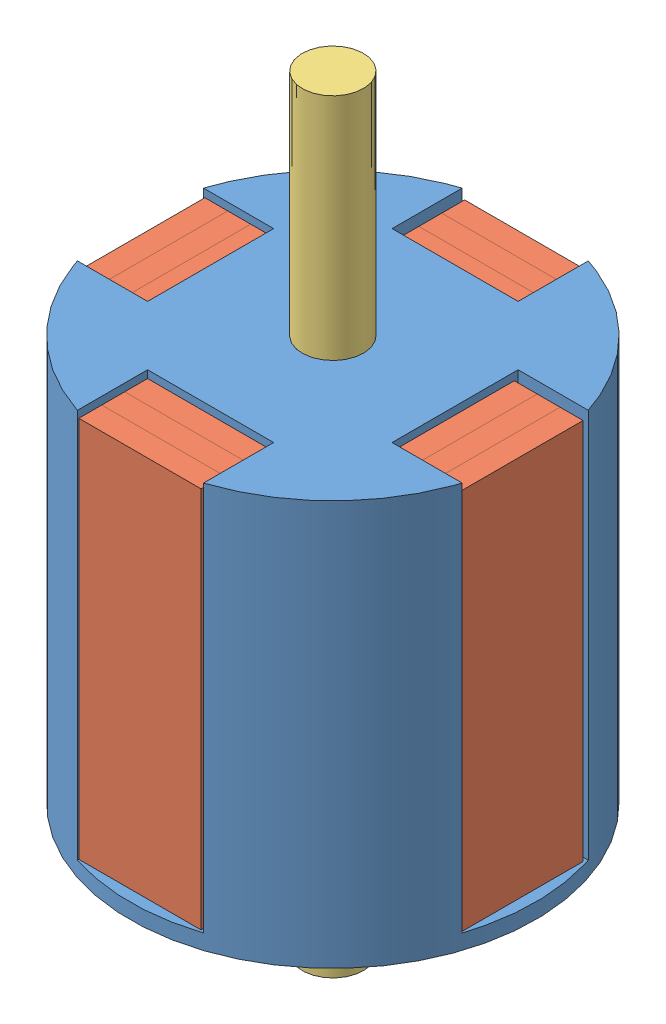
SolidWorks assembly rotor, configuration 默认. Lengths in mm.
Overall size (53 100 53).
14 component instances, 3 part files, 8 mates.
Components (placement in the parent):
- inner rotor-1: inner rotor [默认] at (-18.2401 -31.003 53.0001) size (53 53 53)
- magnet x12个 rectangular new-1: magnet x12个 rectangular new [默认] at (-18.4901 -6.003 72.0001) x (1 0 0) z (0 1 0) size (16 3 50)
- magnet x12个 rectangular new-2: magnet x12个 rectangular new [默认] at (-18.4901 -6.003 75.0001) x (1 0 0) z (0 1 0) size (16 3 50)
- magnet x12个 rectangular new-3: magnet x12个 rectangular new [默认] at (-18.4901 -6.003 78.0001) x (1 0 0) z (0 1 0) size (16 3 50)
- magnet x12个 rectangular new-4: magnet x12个 rectangular new [默认] at (-17.9901 -6.003 34) x (-1 0 0) z (0 1 0) size (16 3 50)
- magnet x12个 rectangular new-5: magnet x12个 rectangular new [默认] at (-17.9901 -6.003 31.0001) x (-1 0 0) z (0 1 0) size (16 3 50)
- magnet x12个 rectangular new-6: magnet x12个 rectangular new [默认] at (-17.9901 -6.003 28) x (-1 0 0) z (0 1 0) size (16 3 50)
- magnet x12个 rectangular new-7: magnet x12个 rectangular new [默认] at (-34.2401 -6.003 52.7501) x (0 0 -1) z (0 1 0) size (16 3 50)
- magnet x12个 rectangular new-8: magnet x12个 rectangular new [默认] at (-37.2401 -6.003 52.7501) x (0 0 -1) z (0 1 0) size (16 3 50)
- magnet x12个 rectangular new-9: magnet x12个 rectangular new [默认] at (-40.2401 -6.003 52.7501) x (0 0 -1) z (0 1 0) size (16 3 50)
- magnet x12个 rectangular new-10: magnet x12个 rectangular new [默认] at (-2.2401 -6.003 53.2501) x (0 0 1) z (0 1 0) size (16 3 50)
- magnet x12个 rectangular new-11: magnet x12个 rectangular new [默认] at (0.7599 -6.003 53.2501) x (0 0 1) z (0 1 0) size (16 3 50)
- magnet x12个 rectangular new-12: magnet x12个 rectangular new [默认] at (3.7599 -6.003 53.2501) x (0 0 1) z (0 1 0) size (16 3 50)
- 8mm shaft-1: 8mm shaft [默认] at (-18.2401 -50.003 53.0001) x (0.206718 0 -0.978401) z (0.978401 0 0.206718) size (8 100 8)
Mates (geometry in assembly coordinates):
- Coincident1: coincident anti-aligned: plane of inner rotor-1 through (-9.9901 19.997 69) normal (0 0 1); plane of magnet x12个 rectangular new-1 through (-18.4901 -6.003 69) normal (0 0 -1)
- Coincident2: coincident anti-aligned: plane of inner rotor-1 through (-18.2401 -31.003 53.0001) normal (0 1 0); plane of magnet x12个 rectangular new-1 through (-10.4901 -31.003 69) normal (0 -1 0)
- Coincident3: coincident anti-aligned: plane of inner rotor-1 through (-26.4901 19.997 78.1831) normal (1 0 0); plane of magnet x12个 rectangular new-1 through (-26.4901 18.997 69) normal (-1 0 0)
- Coincident4: coincident anti-aligned: plane of inner rotor-1 through (-34.2401 19.997 61.2501) normal (-1 0 0); plane of magnet x12个 rectangular new-7 through (-34.2401 -6.003 52.7501) normal (1 0 0)
- Coincident5: coincident anti-aligned: plane of inner rotor-1 through (-18.2401 -31.003 53.0001) normal (0 1 0); plane of magnet x12个 rectangular new-7 through (-37.2401 -31.003 44.7501) normal (0 -1 0)
- Coincident6: coincident anti-aligned: plane of inner rotor-1 through (-43.4232 19.997 44.7501) normal (0 0 1); plane of magnet x12个 rectangular new-7 through (-37.2401 18.997 44.7501) normal (0 0 -1)
- Concentric1: concentric: cylinder of inner rotor-1 through (-18.2401 -33.003 53.0001) axis (0 1 0) radius 4; cylinder of 8mm shaft-1 through (-18.2401 43.6553 53.0001) axis (0 -1 0) radius 4
- Distance1: distance = 30 mm aligned: plane of inner rotor-1 through (-18.2401 19.997 53.0001) normal (0 1 0); plane of 8mm shaft-1 through (-18.2401 49.997 53.0001) normal (0 1 0)
